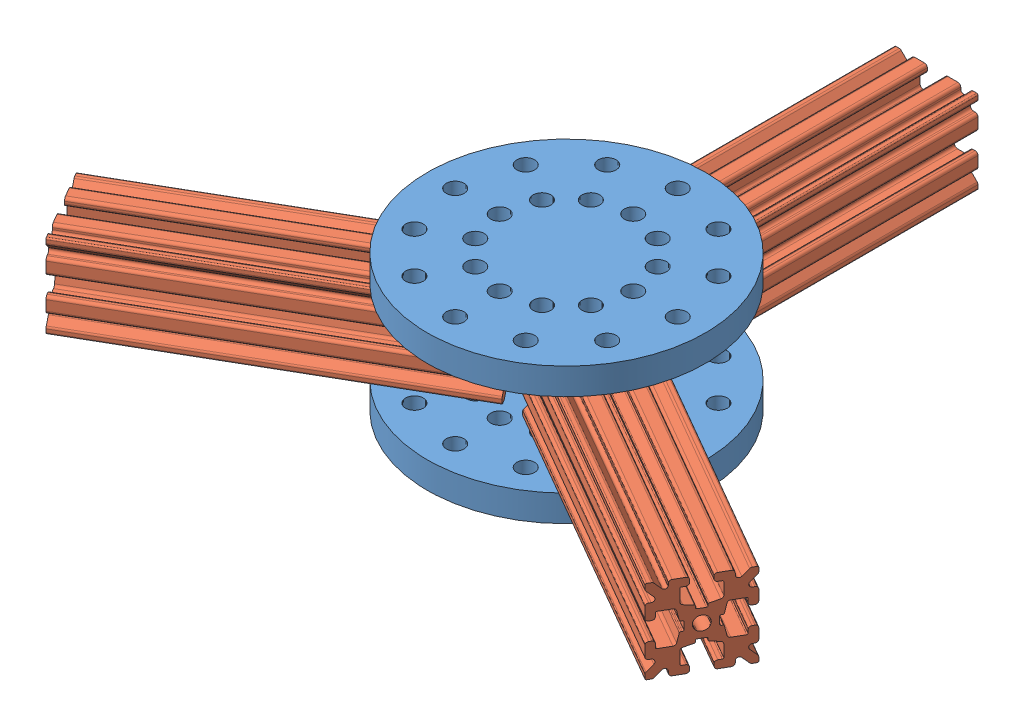
SolidWorks assembly spoke_example, configuration Default. Lengths in mm.
Overall size (122.62 24.52 106.2).
5 component instances, 2 part files, 5 mates.
Components (placement in the parent):
- spoke_hub-1: spoke_hub [Default] at (-3.8754 0.3402 1.8139) size (50 4.76 50)
- OpenBeam 1515 Aluminum Extrusion-1: OpenBeam 1515 Aluminum Extrusion [60 mm] at (-3.8754 12.6027 -4.6534) size (15 15 60)
- OpenBeam 1515 Aluminum Extrusion-2: OpenBeam 1515 Aluminum Extrusion [60 mm] at (1.7254 12.6027 5.0475) x (-0.5 0 0.866025) z (-0.866025 0 -0.5) size (15 15 60)
- OpenBeam 1515 Aluminum Extrusion-3: OpenBeam 1515 Aluminum Extrusion [60 mm] at (-9.4762 12.6027 5.0475) x (-0.5 0 -0.866025) z (0.866025 0 -0.5) size (15 15 60)
- spoke_hub-2: spoke_hub [Default] at (-3.8754 20.1027 1.8139) size (50 4.76 50)
Mates (geometry in assembly coordinates):
- Coincident1: coincident anti-aligned: plane of spoke_hub-1 through (-3.8754 5.1027 1.8139) normal (0 1 0); plane of OpenBeam 1515 Aluminum Extrusion-1 through (-1.7754 5.1027 -64.6534) normal (0 -1 0)
- Coincident2: coincident aligned: plane of spoke_hub-1 through (-3.8754 0.3402 1.8139) normal (1 0 0); plane of OpenBeam 1515 Aluminum Extrusion-1 through (-3.8754 12.6027 -4.6534) normal (1 0 0)
- Coincident3: coincident anti-aligned: plane of OpenBeam 1515 Aluminum Extrusion-1 through (-5.9754 20.1027 -64.6534) normal (0 1 0); plane of spoke_hub-2 through (-3.8754 20.1027 1.8139) normal (0 -1 0)
- Concentric1: concentric aligned: cylinder of spoke_hub-1 through (-3.8754 5.1027 1.8139) axis (0 -1 0) radius 25; cylinder of spoke_hub-2 through (-3.8754 24.8652 1.8139) axis (0 -1 0) radius 25
- Concentric2: concentric aligned: cylinder of spoke_hub-1 through (-21.1959 5.1027 -8.1861) axis (0 -1 0) radius 1.6; cylinder of spoke_hub-2 through (-21.1959 24.8652 -8.1861) axis (0 -1 0) radius 1.6
